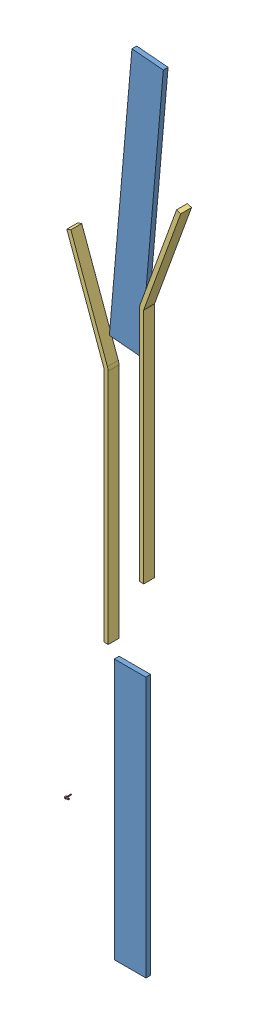
SolidWorks assembly conveyor_145x1200_complete, configuration Domyślna. Lengths in mm.
Overall size (1226.45 3675.1 53.09).
7 component instances, 4 part files, 10 mates.
Components (placement in the parent):
- Belt Conveyor.step-1: Belt Conveyor.step [Domyślna] at (-64.4362 912.0124 3281.4657) (suppressed, hidden)
- brd-145x1200-1: brd-145x1200 [Default] at (-23.2618 -1411.1394 3822.6198) x (0 -1 -0.000614) z (0 -0.000614 1) size (1200 145 22)
- FU-R67TZ-1: FU-R67TZ [Default] at (-303.4136 -1473.5631 3846.1036) size (16.81 11.5 30)
- Część191^conveyor_145x1200_complete-1: Część191^conveyor_145x1200_complete [Domyślna] at origin (virtual)
- prowadnica-1: prowadnica [Domyślna] at (144.1402 914.2257 3824.047) x (-0.34202 -0.939692 -0.000577) z (0 -0.000614 1) size (1532.53 393.44 50)
- prowadnica-2: prowadnica [Domyślna] at (-190.6638 590.6895 3873.8485) x (0.34202 -0.939692 -0.000577) z (0 0.000614 -1) size (1532.53 393.44 50)
- brd-145x1200-2: brd-145x1200 [Default] at (6.841 1059.916 3824.1364) x (-0.087156 -0.996195 -0.000611) z (0 -0.000614 1) size (1200 145 22)
Mates (geometry in assembly coordinates):
- Równolegle1: parallel anti-aligned: line of Belt Conveyor.step-1/Belt doang v4.step-1 through (218.6326 1632.3847 3824.4878) axis (0 -1 -0.000614); line of brd-145x1200-1 through (49.2382 -2011.1528 3844.2516) axis (0 1 0.000614)
- Wspólnie2: coincident anti-aligned: plane of Belt Conveyor.step-1/Belt doang v4.step-1 through (218.6326 -1543.8403 3822.5384) normal (0 -0.000614 1); plane of brd-145x1200-1 through (-95.7618 -2011.1393 3822.2516) normal (0 0.000614 -1)
- Wspólnie3: coincident anti-aligned: plane of Belt Conveyor.step-1/8260K11_Mounted Bearing with Three-Bolt Flange.step-1/8260K11_Mounted Bearing with Three-Bolt Flange(Mirror) (3).step-1/8260K11_Mounted Bearing with Three-Bolt Flange(Mirror) (3)-14.step-1 through (-311.3672 -1378.6233 3821.1036) normal (0 0 1); plane of FU-R67TZ-1 through (-316.8136 -1474.6641 3821.1036) normal (0 0 -1)
- Wspólnie5: coincident anti-aligned: plane of Belt Conveyor.step-1/Belt doang v4.step-1 through (218.6326 -1543.8403 3822.5384) normal (0 -0.000614 1); plane of prowadnica-1 through (144.1402 914.2257 3824.047) normal (0 0.000614 -1)
- Wspólnie6: coincident anti-aligned: line of brd-145x1200-1 through (49.2382 -2011.1393 3822.2516) axis (0 1 0.000614); line of prowadnica-1 through (49.2382 673.9064 3823.8995) axis (0 -1 -0.000614)
- Wspólnie7: coincident anti-aligned: plane of Belt Conveyor.step-1/Belt doang v4.step-1 through (218.6326 -1543.8403 3822.5384) normal (0 -0.000614 1); plane of prowadnica-2 through (-190.6638 590.7202 3823.8485) normal (0 0.000614 -1)
- Równolegle2: parallel aligned: line of brd-145x1200-1 through (-95.7618 -811.1395 3822.9881) axis (0 -1 -0.000614); line of prowadnica-2 through (-95.7618 350.3702 3873.701) axis (0 -1 -0.000614)
- Wspólnie9: coincident anti-aligned: plane of brd-145x1200-1 through (-95.7618 -2011.1528 3844.2516) normal (-1 0 0); plane of prowadnica-2 through (-95.7618 359.2172 3823.7064) normal (1 0 0)
- Wspólnie11: coincident anti-aligned: plane of Belt Conveyor.step-1/Belt doang v4.step-1 through (218.6326 -1543.8403 3822.5384) normal (0 -0.000614 1); plane of brd-145x1200-2 through (-117.6766 468.5181 3823.7735) normal (0 0.000614 -1)
- Kąt1: planar angle = 0.436332 rad aligned: line of brd-145x1200-2 through (-13.0897 1663.938 3846.5072) axis (-0.087156 -0.996195 -0.000611); line of prowadnica-2 through (-266.7719 829.0635 3823.9948) axis (0.34202 -0.939692 -0.000577)
